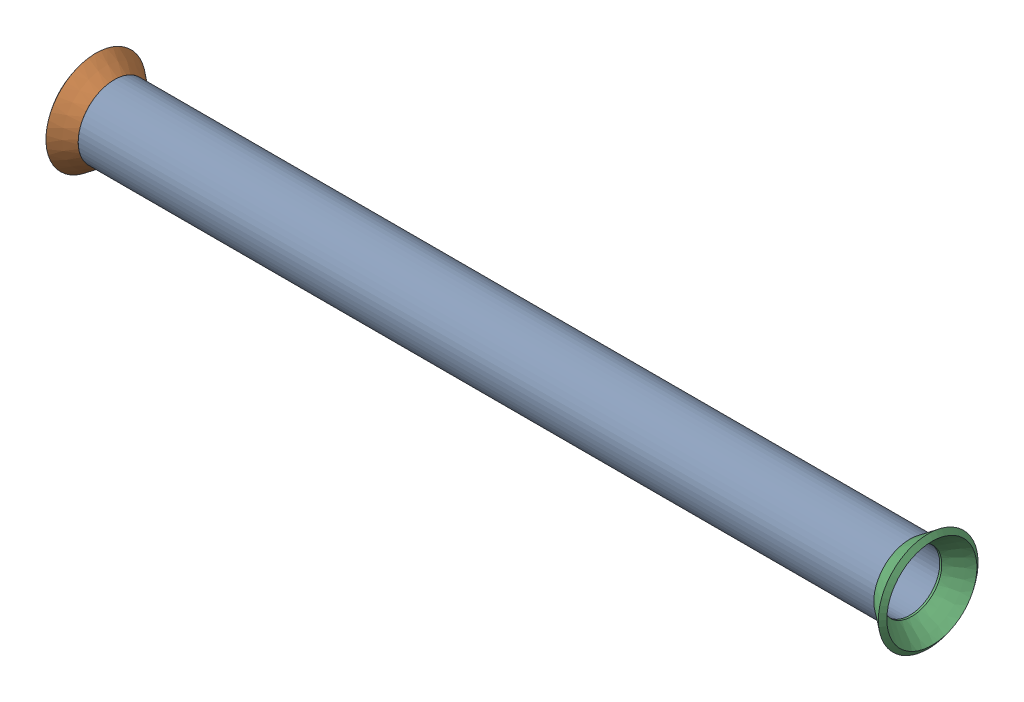
SolidWorks assembly Pipe 49, configuration Default. Lengths in mm.
Overall size (148.14 22.99 22.99).
3 component instances, 2 part files, 2 mates.
Components (placement in the parent):
- Part14-1: Part14 [Default<As Machined>] at (-870.9999 -1071.2689 485.9354) x (-1 0 0) z (0 0 -1) size (140.37 12.7 12.7)
- Flared pipe end - .5 inch-1: Flared pipe end - .5 inch [Default<As Machined>] at (-904.8327 400.5908 485.9354) x (0 0.383049 -0.923728) z (-1 0 0) size (17.59 17.59 3.89)
- Flared pipe end - .5 inch-3: Flared pipe end - .5 inch [Default<As Machined>] at (-764.4659 400.5908 485.9354) x (0 0.383049 0.923728) z (1 0 0) size (17.59 17.59 3.89)
Mates (geometry in assembly coordinates):
- Coincident1567: coincident: circle of Part14-1; circle of Flared pipe end - .5 inch-1
- Concentric848: concentric: circle of Part14-1; circle of Flared pipe end - .5 inch-3
